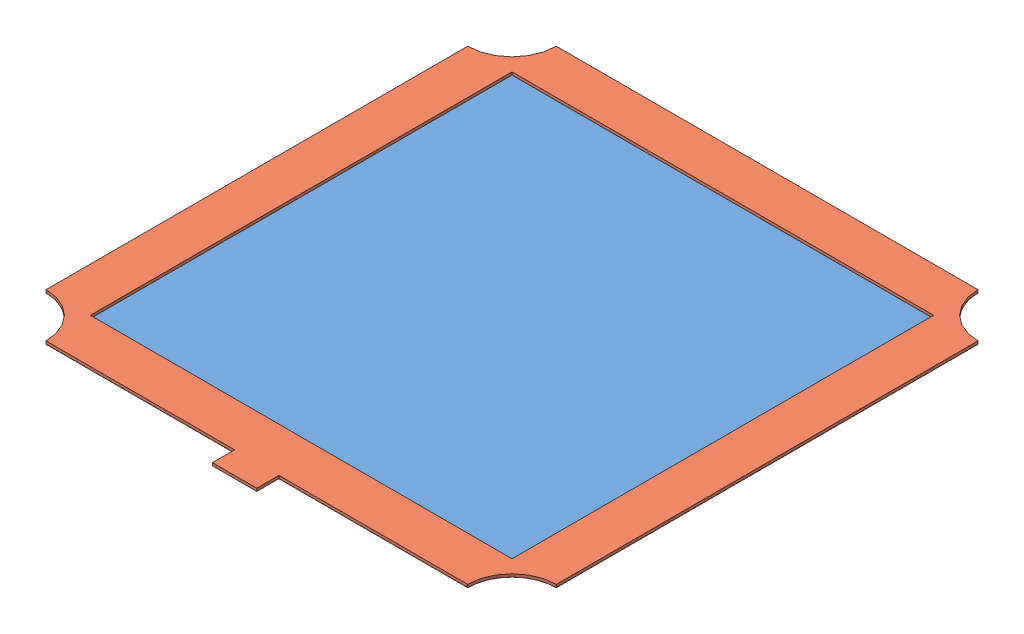
SolidWorks assembly MeshBus, configuration Default. Lengths in mm.
Overall size (146.05 0.85 152.4).
2 component instances, 2 part files, 2 mates.
Components (placement in the parent):
- 9225T321_Acid-Resistant 400 Nickel Wire Cloth-1: 9225T321_Acid-Resistant 400 Nickel Wire Cloth [9225T321] at (-50.5853 15.5951 16.0981) size (146.05 0.05 146.05)
- CopperBus-1: CopperBus [Default] at (-63.3029 16.4205 -1.338) x (1 0 0) z (0 0 -1) size (146.05 0.8 152.4)
Mates (geometry in assembly coordinates):
- Coincident20: coincident: plane of 9225T321_Acid-Resistant 400 Nickel Wire Cloth-1 through (25.6147 15.6205 92.2981) normal (0 1 0); plane of CopperBus-1 through (-56.9529 15.6205 5.012) normal (0 -1 0)
- Concentric1: concentric aligned: circle of 9225T321_Acid-Resistant 400 Nickel Wire Cloth-1; circle of CopperBus-1
